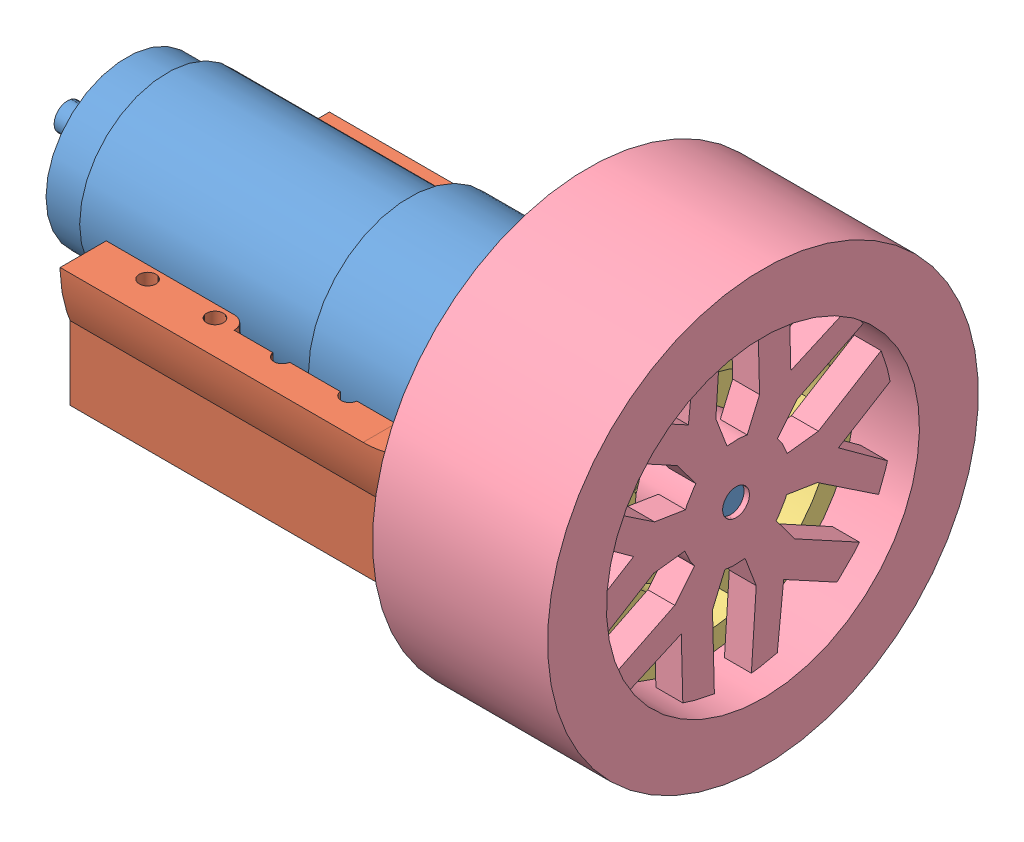
SolidWorks assembly BigRobotMotorBlockLeftAssembly, configuration Default. Lengths in mm.
Overall size (103.3 87.89 87.89).
4 component instances, 4 part files, 6 mates.
Components (placement in the parent):
- 2642W_CR_with_30-1S-1: 2642W_CR_with_30-1S [Défaut] at (-28.6404 52.7391 83.2255) size (98.5 30 30)
- BigRobotMotorSupport-1: BigRobotMotorSupport [Default] at (-9.7404 52.7391 83.2255) x (0 0 -1) z (1 0 0) size (40 38.5 65)
- BigRobotWheelHub-1: BigRobotWheelHub [Default] at (49.2596 52.7391 83.2255) x (0 0.797707 -0.603046) z (0 -0.603046 -0.797707) size (47 17.4 47)
- Wheel-Traction-63x26mm-1: Wheel-Traction-63x26mm [Défaut] at (48.6596 52.7391 83.2255) x (0 -0.85563 0.517588) z (1 0 0) size (64 64 26)
Mates (geometry in assembly coordinates):
- Coincident2: coincident anti-aligned: plane of 2642W_CR_with_30-1S-1 through (49.2596 61.7391 83.2255) normal (1 0 0); plane of BigRobotMotorSupport-1 through (49.2596 52.7391 83.2255) normal (-1 0 0)
- Concentric1: concentric aligned: cylinder of 2642W_CR_with_30-1S-1 through (-28.6404 52.7391 83.2255) axis (-1 0 0) radius 9; cylinder of BigRobotMotorSupport-1 through (55.2596 52.7391 83.2255) axis (-1 0 0) radius 9.2
- Concentric2: concentric anti-aligned: cylinder of 2642W_CR_with_30-1S-1 through (-28.6404 52.7391 83.2255) axis (-1 0 0) radius 4; cylinder of BigRobotWheelHub-1 through (68.1596 52.7391 83.2255) axis (1 0 0) radius 4.1
- Coincident3: coincident aligned: plane of BigRobotMotorSupport-1 through (49.2596 52.7391 83.2255) normal (-1 0 0); plane of BigRobotWheelHub-1 through (49.2596 56.0097 80.753) normal (-1 0 0)
- Concentric3: concentric: cone of BigRobotWheelHub-1 through (49.2596 52.7391 83.2255) axis (1 0 0); cylinder of Wheel-Traction-63x26mm-1 through (99.9534 52.7391 83.2255) axis (1 0 0) radius 23.25
- Coincident4: coincident anti-aligned: plane of BigRobotWheelHub-1 through (66.6596 52.7391 83.2255) normal (1 0 0); plane of Wheel-Traction-63x26mm-1 through (66.6596 52.7391 83.2255) normal (-1 0 0)
